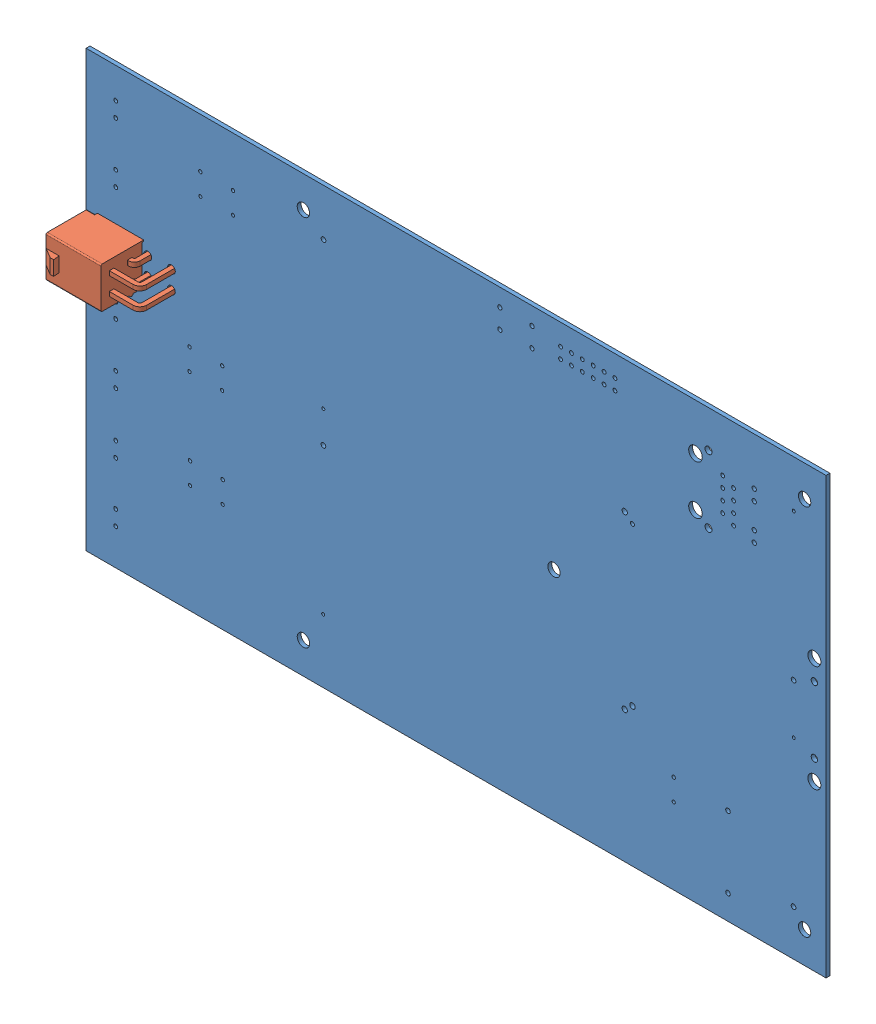
SolidWorks assembly PCB, configuration Default. Lengths in mm.
Overall size (172.72 101.6 16.27).
112 component instances, 15 part files, 0 mates.
Components (placement in the parent):
- Revised Board-1: Revised Board [Default] at (0 0 -0.8966) size (172.72 101.6 0.91)
- FB5-1: FB5 [Default] at origin
  - 506292128-1: 506292128 [Default] at (256.667 117.094 0.0127)
    - Extruded-1: Extruded [Default] at origin (suppressed, hidden)
- SATA1-1: SATA1 [Default] at origin size (56.51 47.45 7.82) (suppressed, hidden)
- FB12-1: FB12 [Default] at origin
  - 506292128-1: 506292128 [Default] at (285.75 103.124 0.0127)
    - Extruded-1: Extruded [Default] at origin (suppressed, hidden)
- POWER-1: POWER [Default] at origin size (19.94 10 15)
  - 039300040-1: 039300040 [Default] at (114.9497 138.4306 0.0127) x (0 -1 0) z (-1 0 0) size (10 15 19.94)
    - Open CASCADE STEP translator 6.2 18.5.1.1-1: Open CASCADE STEP translator 6.2 18.5.1.1 [Default] at origin size (10 15 19.94)
- BATTERY-1: BATTERY [Default] at origin
  - 506290848-1: 506290848 [Default] at (264.16 79.248 0.0127)
    - Extruded_1-1: Extruded_1 [Default] at origin (suppressed, hidden)
  - 506290720-1: 506290720 [Default] at (264.16 78.994 0.0127)
    - Extruded_2-1: Extruded_2 [Default] at origin (suppressed, hidden)
  - 506290592-1: 506290592 [Default] at (264.16 87.63 7.9629)
    - Extruded_3-1: Extruded_3 [Default] at origin (suppressed, hidden)
  - 506291360-1: 506291360 [Default] at (264.16 90.17 0.0127)
    - Extruded_4-1: Extruded_4 [Default] at origin (suppressed, hidden)
  - 506291232-1: 506291232 [Default] at (264.16 90.17 0.0127)
    - Extruded_5-1: Extruded_5 [Default] at origin (suppressed, hidden)
- Reset-1: Reset [Default] at origin size (6.25 6.25 5) (suppressed, hidden)
- FB6-1: FB6 [Default] at origin
  - 506292128-1: 506292128 [Default] at (261.747 117.094 0.0127)
    - Extruded-1: Extruded [Default] at origin (suppressed, hidden)
- FB7-1: FB7 [Default] at origin
  - 506292128-1: 506292128 [Default] at (266.827 117.094 0.0127)
    - Extruded-1: Extruded [Default] at origin (suppressed, hidden)
- FB8-1: FB8 [Default] at origin
  - 506292128-1: 506292128 [Default] at (269.24 132.08 0.0127)
    - Extruded-1: Extruded [Default] at origin (suppressed, hidden)
- FB9-1: FB9 [Default] at origin
  - 506292128-1: 506292128 [Default] at (264.16 139.7 0.0127)
    - Extruded-1: Extruded [Default] at origin (suppressed, hidden)
- FB10-1: FB10 [Default] at origin
  - 506292128-1: 506292128 [Default] at (261.62 132.08 0.0127)
    - Extruded-1: Extruded [Default] at origin (suppressed, hidden)
- FB11-1: FB11 [Default] at origin
  - 506292128-1: 506292128 [Default] at (256.54 132.08 0.0127)
    - Extruded-1: Extruded [Default] at origin (suppressed, hidden)
- U1-1: U1 [Default] at origin size (3.9 8.65 1.75) (suppressed, hidden)
- VGA1-1: VGA1 [Default] at origin size (22.01 30.8 16) (suppressed, hidden)
- X1-1: X1 [Default] at origin
  - 506290976-1: 506290976 [Default] at (259.2025 158.75 0.0127)
    - Extruded_10-1: Extruded_10 [Default] at origin (suppressed, hidden)
- FB1_1-1: FB1_1 [Default] at origin
  - 506292000-1: 506292000 [Default] at (132.08 80.01 -1.8466)
    - Extruded_11-1: Extruded_11 [Default] at origin (suppressed, hidden)
- FB1_2-1: FB1_2 [Default] at origin
  - 506292000-1: 506292000 [Default] at (132.08 107.95 -1.8466)
    - Extruded_11-1: Extruded_11 [Default] at origin (suppressed, hidden)
- FB1_3-1: FB1_3 [Default] at origin
  - 506291872-1: 506291872 [Default] at (132.08 148.59 -1.8466)
    - Extruded_12-1: Extruded_12 [Default] at origin (suppressed, hidden)
- FB2_1-1: FB2_1 [Default] at origin
  - 506292000-1: 506292000 [Default] at (132.08 88.9 -1.8466)
    - Extruded_11-1: Extruded_11 [Default] at origin (suppressed, hidden)
- FB2_2-1: FB2_2 [Default] at origin
  - 506291872-1: 506291872 [Default] at (132.08 116.84 -1.8466)
    - Extruded_12-1: Extruded_12 [Default] at origin (suppressed, hidden)
- FB2_3-1: FB2_3 [Default] at origin
  - 506291872-1: 506291872 [Default] at (132.08 156.21 -1.8466)
    - Extruded_12-1: Extruded_12 [Default] at origin (suppressed, hidden)
- FB3_1-1: FB3_1 [Default] at origin
  - 506292000-1: 506292000 [Default] at (132.08 93.98 -1.8466)
    - Extruded_11-1: Extruded_11 [Default] at origin (suppressed, hidden)
- FB3_2-1: FB3_2 [Default] at origin
  - 506291872-1: 506291872 [Default] at (132.08 121.92 -1.8466)
    - Extruded_12-1: Extruded_12 [Default] at origin (suppressed, hidden)
- FB3_3-1: FB3_3 [Default] at origin
  - 506291872-1: 506291872 [Default] at (132.08 162.56 -1.8466)
    - Extruded_12-1: Extruded_12 [Default] at origin (suppressed, hidden)
- FB4_1-1: FB4_1 [Default] at origin
  - 506292128-1: 506292128 [Default] at (128.27 100.33 -1.8466)
    - Extruded-1: Extruded [Default] at origin (suppressed, hidden)
- FB4_2-1: FB4_2 [Default] at origin
  - 506291872-1: 506291872 [Default] at (132.08 129.54 -1.8466)
    - Extruded_12-1: Extruded_12 [Default] at origin (suppressed, hidden)
- FB4_3-1: FB4_3 [Default] at origin
  - 506292000-1: 506292000 [Default] at (132.334 170.18 -1.8466)
    - Extruded_11-1: Extruded_11 [Default] at origin (suppressed, hidden)
- IC1_1-1: IC1_1 [Default] at origin
  - 506291488-1: 506291488 [Default] at (154.94 101.6 -2.6266)
    - Extruded_13-1: Extruded_13 [Default] at origin (suppressed, hidden)
- IC1_2-1: IC1_2 [Default] at origin
  - 506291488-1: 506291488 [Default] at (154.94 118.11 -2.6266)
    - Extruded_13-1: Extruded_13 [Default] at origin (suppressed, hidden)
- IC1_3-1: IC1_3 [Default] at origin
  - 506291744-1: 506291744 [Default] at (158.75 156.21 -2.6266)
    - Extruded_14-1: Extruded_14 [Default] at origin (suppressed, hidden)
- J1-1: J1 [Default] at origin size (9 9.9 4.47)
  - UX60-MB-5ST_1-1: UX60-MB-5ST_1 [Default] at (163.2375 87.52 43.1834) x (-1 0 0) z (0 -1 0) size (9 4.47 9.9)
    - ux60-mb-5sT-1: ux60-mb-5sT [Default] at (39.3275 -4.7664 57.125) x (0 0 -1) z (1 0 0) size (9.9 4.47 9)
- J2-1: J2 [Default] at origin size (9 9.9 4.47)
  - UX60-MB-5ST_1-1: UX60-MB-5ST_1 [Default] at (163.2375 101.363 43.1834) x (-1 0 0) z (0 -1 0) size (9 4.47 9.9)
    - ux60-mb-5sT-1: ux60-mb-5sT [Default] at (39.3275 -4.7664 57.125) x (0 0 -1) z (1 0 0) size (9.9 4.47 9)
- J3-1: J3 [Default] at origin size (9 9.9 4.47)
  - UX60-MB-5ST_1-1: UX60-MB-5ST_1 [Default] at (163.2375 115.46 43.1834) x (-1 0 0) z (0 -1 0) size (9 4.47 9.9)
    - ux60-mb-5sT-1: ux60-mb-5sT [Default] at (39.3275 -4.7664 57.125) x (0 0 -1) z (1 0 0) size (9.9 4.47 9)
- J4-1: J4 [Default] at origin size (9 9.9 4.47)
  - UX60-MB-5ST_1-1: UX60-MB-5ST_1 [Default] at (163.2375 129.43 43.1834) x (-1 0 0) z (0 -1 0) size (9 4.47 9.9)
    - ux60-mb-5sT-1: ux60-mb-5sT [Default] at (39.3275 -4.7664 57.125) x (0 0 -1) z (1 0 0) size (9.9 4.47 9)
- J5-1: J5 [Default] at origin size (9 9.9 4.47)
  - UX60-MB-5ST_1-1: UX60-MB-5ST_1 [Default] at (163.2375 156.1 43.1834) x (-1 0 0) z (0 -1 0) size (9 4.47 9.9)
    - ux60-mb-5sT-1: ux60-mb-5sT [Default] at (39.3275 -4.7664 57.125) x (0 0 -1) z (1 0 0) size (9.9 4.47 9)
- J6-1: J6 [Default] at origin size (9 9.9 4.47)
  - UX60-MB-5ST_1-1: UX60-MB-5ST_1 [Default] at (163.2375 170.07 43.1834) x (-1 0 0) z (0 -1 0) size (9 4.47 9.9)
    - ux60-mb-5sT-1: ux60-mb-5sT [Default] at (39.3275 -4.7664 57.125) x (0 0 -1) z (1 0 0) size (9.9 4.47 9)
- OR1-1: OR1 [Default] at origin
  - 506292384-1: 506292384 [Default] at (157.48 137.16 -1.9966)
    - Extruded_15-1: Extruded_15 [Default] at origin (suppressed, hidden)
